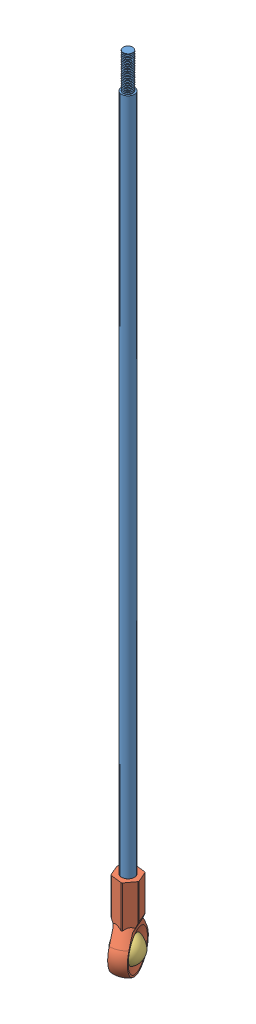
SolidWorks assembly lower_link_assembly, configuration Default. Lengths in mm.
Overall size (17.11 373.5 22.33).
3 component instances, 3 part files, 3 mates.
Components (placement in the parent):
- lower_link-3: lower_link [Default] at (120.1598 -0.7037 372.678) x (-0.322 0 0.94674) z (-0.94674 0 -0.322) size (6 350 6)
- KCRM-06-01-1: KCRM-06-01 [Default] at (120.1598 15.7963 372.678) x (-0.396245 0 -0.918145) z (-0.918145 0 0.396245) size (20 40 10)
- KCRM-06 -02-1: KCRM-06 -02 [Default] at (120.1598 -14.2037 372.678) x (0.982347 0.063485 0.175965) z (0.178663 -0.039639 -0.983112) size (12.7 12.7 9)
Mates (geometry in assembly coordinates):
- Concentric8: concentric: sphere of KCRM-06-01-1; sphere of KCRM-06 -02-1
- Concentric9: concentric aligned: cylinder of lower_link-3 through (120.1598 15.7963 372.678) axis (0 -1 0) radius 2.25; cylinder of KCRM-06-01-1 through (120.1598 15.7963 372.678) axis (0 -1 0) radius 2.4585
- Coincident8: coincident anti-aligned: plane of lower_link-3 through (120.1598 15.7963 372.678) normal (0 -1 0); plane of KCRM-06-01-1 through (120.1598 15.7963 372.678) normal (0 1 0)
